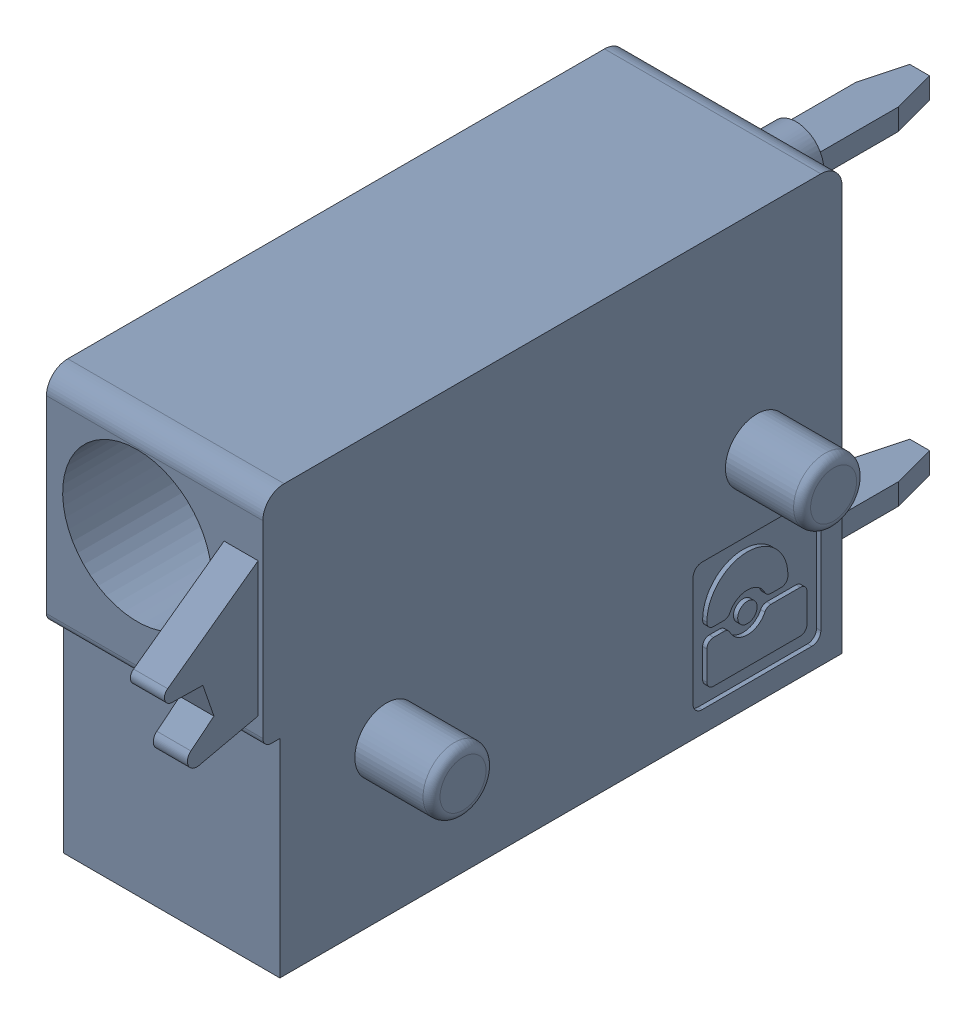
SolidWorks assembly J58, configuration Default. Lengths in mm.
Overall size (6.88 10 19.2).
2 component instances, 1 part files, 0 mates.
Components (placement in the parent):
- 1790348-1: 1790348 [Default] at (172.0851 -7.6199 0) x (0 1 0) z (1 0 0) size (10 19.2 6.88)
  - ffkds-v2-5.08-1: ffkds-v2-5.08 [Default] at (-23.7414 -38.158 -2.54) x (0 -1 0) z (0 0 1) size (19.2 10 6.88)
